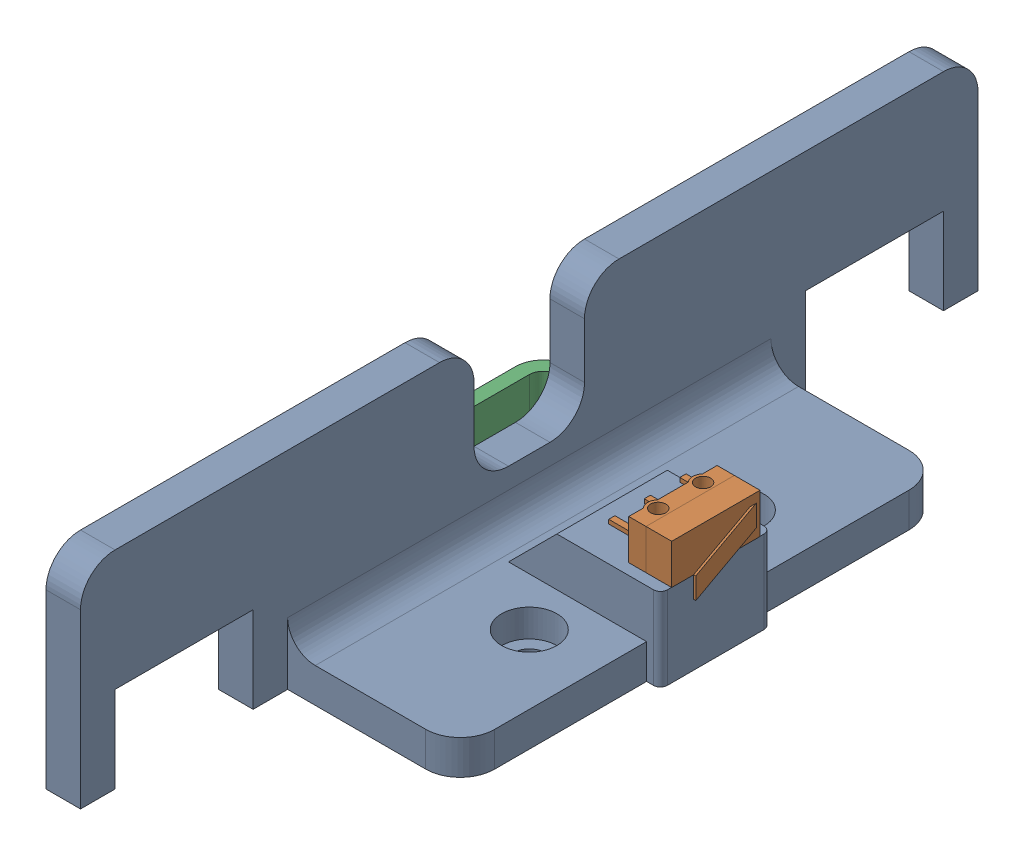
SolidWorks assembly EndStop_YRight, configuration Default. Lengths in mm.
Overall size (44.77 30 130).
3 component instances, 3 part files, 6 mates.
Components (placement in the parent):
- WW0013-1: WW0013 [Default] at origin size (32 30 130)
- Limit Switch-1: Limit Switch [Default] at (2.03 17.8 -6.4) x (0 0 -1) z (-1 0 0) size (14.05 5.8 14.66)
- WW0037_2-1: WW0037_2 [Default] at (-36 6 0) x (0 0 1) z (0 -1 0) size (50 8 10)
Mates (geometry in assembly coordinates):
- Coincident1: coincident anti-aligned: plane of WW0013-1 through (0 12 0) normal (0 1 0); plane of Limit Switch-1 through (-4.19 12 -6.4) normal (0 -1 0)
- Width1: width anti-aligned: plane of WW0013-1 through (-30 12 8) normal (0 0 -1); plane of Limit Switch-1 through (-30 12 -8) normal (0 0 1); plane of WW0013-1 through (-4.19 17.8 6.4) normal (0 0 1); plane of Limit Switch-1 through (-4.19 17.8 -6.4) normal (0 0 -1)
- Concentric1: concentric aligned: cylinder of WW0013-1 through (-3.07 12 3.25) axis (0 1 0) radius 1.65; cylinder of Limit Switch-1 through (-3.07 17.8 3.25) axis (0 1 0) radius 1.1
- Coincident2: coincident anti-aligned: plane of WW0013-1 through (-30 5 -65) normal (-1 0 0); plane of WW0037_2-1 through (-30 1 15) normal (1 0 0)
- Parallel1: parallel anti-aligned: plane of WW0013-1 through (0 0 0) normal (0 -1 0); plane of WW0037_2-1 through (-36 11 0) normal (0 1 0)
- Concentric2: concentric aligned: cylinder of WW0013-1 through (-26.9 6 20) axis (-1 0 0) radius 3.025; cylinder of WW0037_2-1 through (-30.95 6 20) axis (-1 0 0) radius 3.05
